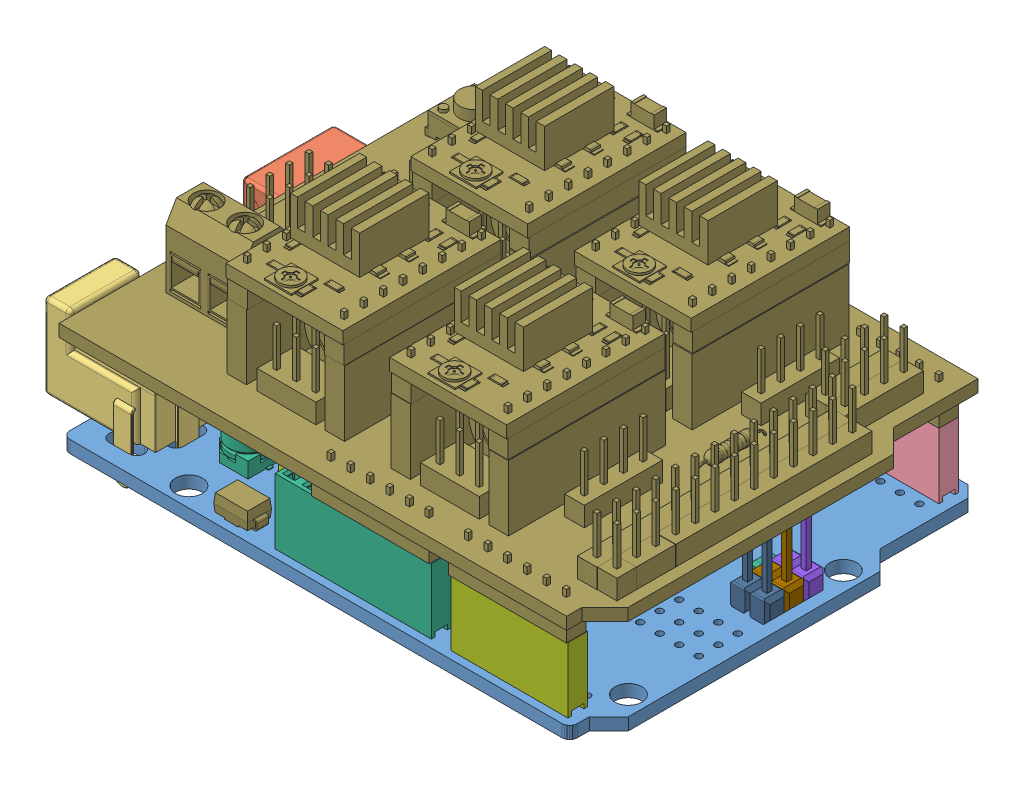
SolidWorks assembly Assem4, configuration Default. Lengths in mm.
Overall size (75.85 35.75 53.57).
50 component instances, 48 part files, 3 mates.
Components (placement in the parent):
- Arduino_Uno-1: Arduino_Uno [Default] at (-3.3078 27.9599 31.7551) x (1 0 0) z (0 1 0) size (75.53 53.3 16.1)
  - Arduino UNO Rev.3 (CH340)-CAWEB.ORG.stp-1: Arduino UNO Rev.3 (CH340)-CAWEB.ORG.stp [Default] at origin size (75.53 53.3 16.1)
    - PCB.stp-1: PCB.stp [Default] at origin size (68.53 53.3 1.6)
    - USB-B.stp-1: USB-B.stp [Default] at origin size (17.02 14.96 14.23)
    - DC_Jack.stp-1: DC_Jack.stp [Default] at origin size (14.5 9.8 16.1)
    - Header female 8.stp-1: Header female 8.stp [Default] at origin size (20.32 2.54 11.7)
    - Header female 10.stp-1: Header female 10.stp [Default] at origin size (25.4 2.54 11.7)
    - Header female 8 (2).stp-1: Header female 8 (2).stp [Default] at origin size (20.32 2.54 11.7)
    - Header female 6.stp-1: Header female 6.stp [Default] at origin size (15.24 2.54 11.7)
    - Header male 2.stp-1: Header male 2.stp [Default] at origin size (5.08 2.54 12.7)
    - Header male 2 (2).stp-1: Header male 2 (2).stp [Default] at origin size (5.08 2.54 12.7)
    - Header male 2 (3).stp-1: Header male 2 (3).stp [Default] at origin size (5.08 2.54 12.7)
    - Atmega328p-AU.stp-1: Atmega328p-AU.stp [Default] at origin size (9 9 1.2)
    - Diode.stp-1: Diode.stp [Default] at origin size (5.3 3.11 2.43)
    - LM358.stp-1: LM358.stp [Default] at origin size (6 4.9 1.75)
    - 16MHZ Crystal.stp-1: 16MHZ Crystal.stp [Default] at origin size (13.58 4.8 3.85)
    - 16MHZ Crystal (2).stp-1: 16MHZ Crystal (2).stp [Default] at origin size (4.8 13.58 3.85)
    - 0603 Package.stp-1: 0603 Package.stp [Default] at origin size (1.05 0.55 0.4)
    - 0603 Package (2).stp-1: 0603 Package (2).stp [Default] at origin size (1.05 0.55 0.4)
    - 0603 Package (3).stp-1: 0603 Package (3).stp [Default] at origin size (1.05 0.55 0.4)
    - 0603 Package (4).stp-1: 0603 Package (4).stp [Default] at origin size (1.05 0.55 0.4)
    - 0603 Package (5).stp-1: 0603 Package (5).stp [Default] at origin size (1.05 0.55 0.4)
    - 0603 Package (6).stp-1: 0603 Package (6).stp [Default] at origin size (1.05 0.55 0.4)
    - 0603 Package (7).stp-1: 0603 Package (7).stp [Default] at origin size (1.05 0.55 0.4)
    - 0603 Package (8).stp-1: 0603 Package (8).stp [Default] at origin size (1.05 0.55 0.4)
    - R1.stp-1: R1.stp [Default] at origin size (1.4 2.66 1.02)
    - 0603 Package (24).stp-1: 0603 Package (24).stp [Default] at origin size (1.05 0.55 0.4)
    - 0603 Package (23).stp-1: 0603 Package (23).stp [Default] at origin size (1.05 0.55 0.4)
    - 0603 Package (22).stp-1: 0603 Package (22).stp [Default] at origin size (1.05 0.55 0.4)
    - 0603 Package (21).stp-1: 0603 Package (21).stp [Default] at origin size (0.55 1.05 0.4)
    - 0603 Package (20).stp-1: 0603 Package (20).stp [Default] at origin size (0.55 1.05 0.4)
    - 0603 Package (19).stp-1: 0603 Package (19).stp [Default] at origin size (0.55 1.05 0.4)
    - 0603 Package (18).stp-1: 0603 Package (18).stp [Default] at origin size (0.55 1.05 0.4)
    - 0603 Package (17).stp-1: 0603 Package (17).stp [Default] at origin size (0.55 1.05 0.4)
    - 0603 Package (16).stp-1: 0603 Package (16).stp [Default] at origin size (0.55 1.05 0.4)
    - 0603 Package (15).stp-1: 0603 Package (15).stp [Default] at origin size (0.55 1.05 0.4)
    - 0603 Package (14).stp-1: 0603 Package (14).stp [Default] at origin size (1.05 0.55 0.4)
    - 0603 Package (13).stp-1: 0603 Package (13).stp [Default] at origin size (1.05 0.55 0.4)
    - 0603 Package (12).stp-1: 0603 Package (12).stp [Default] at origin size (1.05 0.55 0.4)
    - 0603 Package (11).stp-1: 0603 Package (11).stp [Default] at origin size (1.05 0.55 0.4)
    - 0603 Package (10).stp-1: 0603 Package (10).stp [Default] at origin size (1.05 0.55 0.4)
    - 0603 Package (9).stp-1: 0603 Package (9).stp [Default] at origin size (1.05 0.55 0.4)
    - CH340G.stp-1: CH340G.stp [Default] at origin size (9.9 6 1.75)
    - 47uF 27v cap.stp-1: 47uF 27v cap.stp [Default] at origin size (6 5.3 6.22)
    - 47uF 27v cap (2).stp-1: 47uF 27v cap (2).stp [Default] at origin size (6 5.3 6.22)
    - LM1117.stp-1: LM1117.stp [Default] at origin size (7.32 6.7 1.7)
    - Transistor SOC Package.stp-1: Transistor SOC Package.stp [Default] at origin size (2.34 2.92 1)
    - Transistor SOC Package (2).stp-1: Transistor SOC Package (2).stp [Default] at origin size (2.34 2.92 1)
    - A sexy yellow button.stp-1: A sexy yellow button.stp [Default] at origin size (8.4 6.2 3)
- Arduino_Uno_CNC_Shield_V3-1: Arduino_Uno_CNC_Shield_V3 [Default] at (3.0342 39.0099 87.6292) x (1 0 0) z (0 1 0) size (69 53.5 27.15)
Mates (geometry in assembly coordinates):
- Coincident1: coincident: plane of Arduino_Uno-1/Arduino UNO Rev.3 (CH340)-CAWEB.ORG.stp-1/Header female 8.stp-1 through (67.9342 36.4599 35.5592) normal (1 0 0); plane of Arduino_Uno_CNC_Shield_V3-1 through (67.9342 39.0099 35.5592) normal (1 0 0)
- Coincident2: coincident: plane of Arduino_Uno-1/Arduino UNO Rev.3 (CH340)-CAWEB.ORG.stp-1/Header female 8.stp-1 through (52.6942 36.4599 35.5592) normal (0 0 -1); plane of Arduino_Uno_CNC_Shield_V3-1 through (57.7342 37.7349 35.5592) normal (0 0 -1)
- Coincident3: coincident: plane of Arduino_Uno-1/Arduino UNO Rev.3 (CH340)-CAWEB.ORG.stp-1/Header female 8.stp-1 through (51.4242 36.4599 38.0992) normal (0 1 0); plane of Arduino_Uno_CNC_Shield_V3-1 through (57.7342 36.4599 36.8342) normal (0 -1 0)
